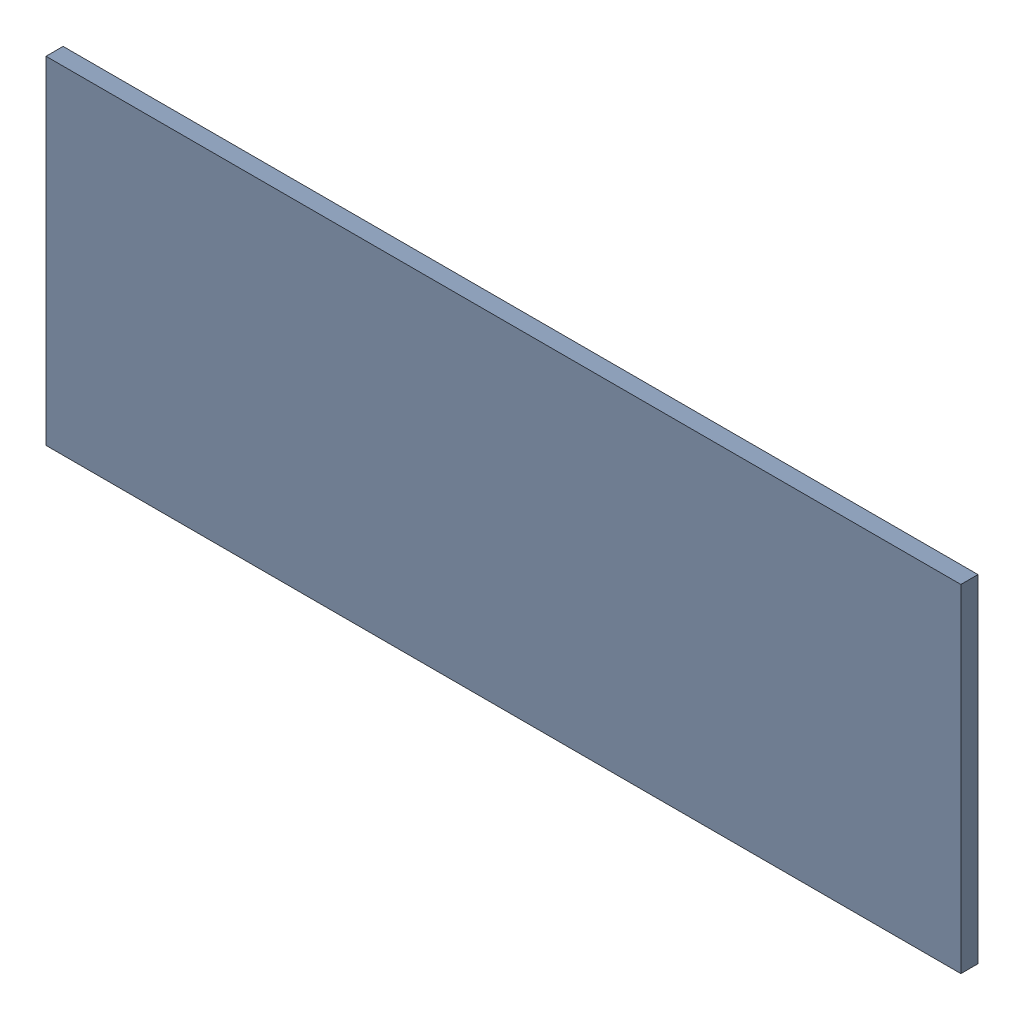
SolidWorks assembly Pad RAK4600-6(14.5mm,21.25mm) on Top Layer, configuration Predeterminado. Lengths in mm.
Overall size (1.9 0.7 0.04).
2 component instances, 1 part files, 0 mates.
Components (placement in the parent):
- Pad RAK4600-6(14.5mm,21.25mm) on Top Layer-1-1: Pad RAK4600-6(14.5mm,21.25mm) on Top Layer-1 [Predeterminado] at (-68.317 -44.187 -0.0457) size (1.9 0.7 0.04)
  - Pad RAK4600-6(14.5mm,21.25mm) on Top Layer-Part-1-1: Pad RAK4600-6(14.5mm,21.25mm) on Top Layer-Part-1 [Predeterminado] at origin size (1.9 0.7 0.04)
